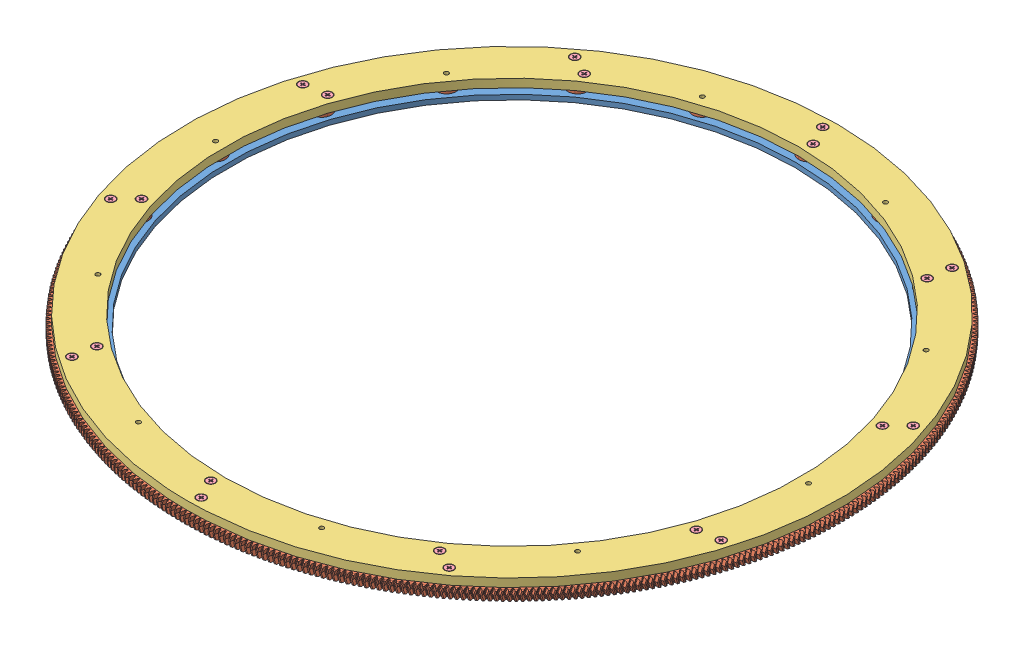
SolidWorks assembly Azimuth Gear, configuration Default. Lengths in mm.
Overall size (765.69 18.86 780.77).
32 component instances, 4 part files, 25 mates.
Components (placement in the parent):
- Center Ring-1: Center Ring [Default] at (-68.2923 13.9978 24.8286) size (660 5 660)
- 450 Teeth Section-1: 450 Teeth Section [Gear Blank] at (-68.2923 16.9978 24.8286) x (0.999972 0 -0.007533) z (0 -1 0) size (199.8 99.77 10.72)
- 450 Teeth Section-2: 450 Teeth Section [Gear Blank] at (-68.2923 16.9978 24.8286) x (0.804566 0 -0.593863) z (0 -1 0) size (199.8 99.77 10.72)
- 450 Teeth Section-3: 450 Teeth Section [Gear Blank] at (-68.2923 16.9978 24.8286) x (0.301844 0 -0.953357) z (0 -1 0) size (199.8 99.77 10.72)
- 450 Teeth Section-4: 450 Teeth Section [Gear Blank] at (-68.2923 16.9978 24.8286) x (-0.316172 0 -0.948702) z (0 -1 0) size (199.8 99.77 10.72)
- 450 Teeth Section-5: 450 Teeth Section [Gear Blank] at (-68.2923 16.9978 24.8286) x (-0.813422 0 -0.581675) z (0 -1 0) size (199.8 99.77 10.72)
- 450 Teeth Section-6: 450 Teeth Section [Gear Blank] at (-68.2923 16.9978 24.8286) x (-0.999972 0 0.007533) z (0 -1 0) size (199.8 99.77 10.72)
- 450 Teeth Section-7: 450 Teeth Section [Gear Blank] at (-68.2923 16.9978 24.8286) x (-0.804566 0 0.593863) z (0 -1 0) size (199.8 99.77 10.72)
- 450 Teeth Section-8: 450 Teeth Section [Gear Blank] at (-68.2923 16.9978 24.8286) x (-0.301844 0 0.953357) z (0 -1 0) size (199.8 99.77 10.72)
- 450 Teeth Section-9: 450 Teeth Section [Gear Blank] at (-68.2923 16.9978 24.8286) x (0.316172 0 0.948702) z (0 -1 0) size (199.8 99.77 10.72)
- 450 Teeth Section-10: 450 Teeth Section [Gear Blank] at (-68.2923 16.9978 24.8286) x (0.813422 0 0.581675) z (0 -1 0) size (199.8 99.77 10.72)
- Spacer ring-1: Spacer ring [Default] at (-68.2923 16.9978 24.8286) size (670 8.5 670)
- flat head screw_am-21: flat head screw_am [B18.6.7M - M4 x 0.7 x 16 Type I Cross Recessed FHMS --16N] at (-375.7267 25.4978 130.2282) x (0 -1 0) z (0 0 1) size (16 8.4 8.4)
- flat head screw_am-22: flat head screw_am [B18.6.7M - M4 x 0.7 x 16 Type I Cross Recessed FHMS --16N] at (-378.9643 25.4978 -70.6068) x (0 -1 0) z (0 0 1) size (16 8.4 8.4)
- flat head screw_am-23: flat head screw_am [B18.6.7M - M4 x 0.7 x 16 Type I Cross Recessed FHMS --16N] at (-263.5358 25.4978 -234.9887) x (0 -1 0) z (0 0 1) size (16 8.4 8.4)
- flat head screw_am-24: flat head screw_am [B18.6.7M - M4 x 0.7 x 16 Type I Cross Recessed FHMS --16N] at (-73.5308 25.4978 -300.1292) x (0 -1 0) z (0 0 1) size (16 8.4 8.4)
- flat head screw_am-25: flat head screw_am [B18.6.7M - M4 x 0.7 x 16 Type I Cross Recessed FHMS --16N] at (118.475 25.4978 -241.1469) x (0 -1 0) z (0 0 1) size (16 8.4 8.4)
- flat head screw_am-26: flat head screw_am [B18.6.7M - M4 x 0.7 x 16 Type I Cross Recessed FHMS --16N] at (239.1421 25.4978 -80.5711) x (0 -1 0) z (0 0 1) size (16 8.4 8.4)
- flat head screw_am-27: flat head screw_am [B18.6.7M - M4 x 0.7 x 16 Type I Cross Recessed FHMS --16N] at (242.3797 25.4978 120.2639) x (0 -1 0) z (0 0 1) size (16 8.4 8.4)
- flat head screw_am-28: flat head screw_am [B18.6.7M - M4 x 0.7 x 16 Type I Cross Recessed FHMS --16N] at (126.9511 25.4978 284.6458) x (0 -1 0) z (0 0 1) size (16 8.4 8.4)
- flat head screw_am-29: flat head screw_am [B18.6.7M - M4 x 0.7 x 16 Type I Cross Recessed FHMS --16N] at (-63.0538 25.4978 349.7863) x (0 -1 0) z (0 0 1) size (16 8.4 8.4)
- flat head screw_am-30: flat head screw_am [B18.6.7M - M4 x 0.7 x 16 Type I Cross Recessed FHMS --16N] at (-255.0596 25.4978 290.804) x (0 -1 0) z (0 0 1) size (16 8.4 8.4)
- flat head screw_am-31: flat head screw_am [B18.6.7M - M4 x 0.7 x 16 Type I Cross Recessed FHMS --16N] at (-359.846 25.4978 114.3909) x (0 -1 0) z (0 0 1) size (16 8.4 8.4)
- flat head screw_am-32: flat head screw_am [B18.6.7M - M4 x 0.7 x 16 Type I Cross Recessed FHMS --16N] at (-356.8077 25.4978 -74.0849) x (0 -1 0) z (0 0 1) size (16 8.4 8.4)
- flat head screw_am-33: flat head screw_am [B18.6.7M - M4 x 0.7 x 16 Type I Cross Recessed FHMS --16N] at (-243.5663 25.4978 -224.7792) x (0 -1 0) z (0 0 1) size (16 8.4 8.4)
- flat head screw_am-34: flat head screw_am [B18.6.7M - M4 x 0.7 x 16 Type I Cross Recessed FHMS --16N] at (-63.3762 25.4978 -280.1318) x (0 -1 0) z (0 0 1) size (16 8.4 8.4)
- flat head screw_am-35: flat head screw_am [B18.6.7M - M4 x 0.7 x 16 Type I Cross Recessed FHMS --16N] at (114.9362 25.4978 -218.9999) x (0 -1 0) z (0 0 1) size (16 8.4 8.4)
- flat head screw_am-36: flat head screw_am [B18.6.7M - M4 x 0.7 x 16 Type I Cross Recessed FHMS --16N] at (223.2614 25.4978 -64.7338) x (0 -1 0) z (0 0 1) size (16 8.4 8.4)
- flat head screw_am-37: flat head screw_am [B18.6.7M - M4 x 0.7 x 16 Type I Cross Recessed FHMS --16N] at (220.2231 25.4978 123.742) x (0 -1 0) z (0 0 1) size (16 8.4 8.4)
- flat head screw_am-38: flat head screw_am [B18.6.7M - M4 x 0.7 x 16 Type I Cross Recessed FHMS --16N] at (106.9816 25.4978 274.4363) x (0 -1 0) z (0 0 1) size (16 8.4 8.4)
- flat head screw_am-39: flat head screw_am [B18.6.7M - M4 x 0.7 x 16 Type I Cross Recessed FHMS --16N] at (-73.2085 25.4978 329.7889) x (0 -1 0) z (0 0 1) size (16 8.4 8.4)
- flat head screw_am-40: flat head screw_am [B18.6.7M - M4 x 0.7 x 16 Type I Cross Recessed FHMS --16N] at (-251.5208 25.4978 268.657) x (0 -1 0) z (0 0 1) size (16 8.4 8.4)
Mates (geometry in assembly coordinates):
- Distance1: distance = 3 mm anti-aligned: plane of Center Ring-1 through (-68.2923 13.9978 24.8286) normal (0 1 0); plane of 450 Teeth Section-1 through (-68.2923 16.9978 24.8286) normal (0 -1 0)
- Concentric1: concentric anti-aligned: circle of Center Ring-1; circle of 450 Teeth Section-1
- Coincident1: coincident anti-aligned: plane of 450 Teeth Section-2 through (132.3859 16.9978 297.2241) normal (0 1 0); plane of Spacer ring-1 through (-68.2923 16.9978 24.8286) normal (0 -1 0)
- Concentric2: concentric anti-aligned: cylinder of Center Ring-1 through (-68.2923 8.9978 24.8286) axis (0 1 0) radius 291; cylinder of Spacer ring-1 through (-68.2923 25.4978 24.8286) axis (0 -1 0) radius 295
- Coincident2: coincident aligned: plane of Center Ring-1 through (-68.2923 13.9978 24.8286) normal (0 0 1); plane of Spacer ring-1 through (-68.2923 16.9978 24.8286) normal (0 0 1)
- Coincident3: coincident aligned: cone of Spacer ring-1 through (-375.7267 25.4978 130.2282) axis (0 -1 0); cone of flat head screw_am-21 through (-375.7267 24.9978 130.2282) axis (0 -1 0)
- Coincident4: coincident aligned: cone of Spacer ring-1 through (-378.9643 25.4978 -70.6068) axis (0 -1 0); cone of flat head screw_am-22 through (-378.9643 24.9978 -70.6068) axis (0 -1 0)
- Coincident5: coincident aligned: cone of Spacer ring-1 through (-263.5358 25.4978 -234.9887) axis (0 -1 0); cone of flat head screw_am-23 through (-263.5358 24.9978 -234.9887) axis (0 -1 0)
- Coincident6: coincident aligned: cone of Spacer ring-1 through (-73.5308 25.4978 -300.1292) axis (0 -1 0); cone of flat head screw_am-24 through (-73.5308 24.9978 -300.1292) axis (0 -1 0)
- Coincident7: coincident aligned: cone of Spacer ring-1 through (118.475 25.4978 -241.1469) axis (0 -1 0); cone of flat head screw_am-25 through (118.475 24.9978 -241.1469) axis (0 -1 0)
- Coincident8: coincident aligned: cone of Spacer ring-1 through (239.1421 25.4978 -80.5711) axis (0 -1 0); cone of flat head screw_am-26 through (239.1421 24.9978 -80.5711) axis (0 -1 0)
- Coincident9: coincident aligned: cone of Spacer ring-1 through (242.3797 25.4978 120.2639) axis (0 -1 0); cone of flat head screw_am-27 through (242.3797 24.9978 120.2639) axis (0 -1 0)
- Coincident10: coincident aligned: cone of Spacer ring-1 through (126.9511 25.4978 284.6458) axis (0 -1 0); cone of flat head screw_am-28 through (126.9511 24.9978 284.6458) axis (0 -1 0)
- Coincident11: coincident aligned: cone of Spacer ring-1 through (-63.0538 25.4978 349.7863) axis (0 -1 0); cone of flat head screw_am-29 through (-63.0538 24.9978 349.7863) axis (0 -1 0)
- Coincident12: coincident aligned: cone of Spacer ring-1 through (-255.0596 25.4978 290.804) axis (0 -1 0); cone of flat head screw_am-30 through (-255.0596 24.9978 290.804) axis (0 -1 0)
- Coincident13: coincident aligned: cone of Spacer ring-1 through (-359.846 25.4978 114.3909) axis (0 -1 0); cone of flat head screw_am-31 through (-359.846 24.9978 114.3909) axis (0 -1 0)
- Coincident14: coincident aligned: cone of Spacer ring-1 through (-356.8077 25.4978 -74.0849) axis (0 -1 0); cone of flat head screw_am-32 through (-356.8077 24.9978 -74.0849) axis (0 -1 0)
- Coincident15: coincident aligned: cone of Spacer ring-1 through (-243.5663 25.4978 -224.7792) axis (0 -1 0); cone of flat head screw_am-33 through (-243.5663 24.9978 -224.7792) axis (0 -1 0)
- Coincident16: coincident aligned: cone of Spacer ring-1 through (-63.3762 25.4978 -280.1318) axis (0 -1 0); cone of flat head screw_am-34 through (-63.3762 24.9978 -280.1318) axis (0 -1 0)
- Coincident17: coincident aligned: cone of Spacer ring-1 through (114.9362 25.4978 -218.9999) axis (0 -1 0); cone of flat head screw_am-35 through (114.9362 24.9978 -218.9999) axis (0 -1 0)
- Coincident18: coincident aligned: cone of Spacer ring-1 through (223.2614 25.4978 -64.7338) axis (0 -1 0); cone of flat head screw_am-36 through (223.2614 24.9978 -64.7338) axis (0 -1 0)
- Coincident19: coincident aligned: cone of Spacer ring-1 through (220.2231 25.4978 123.742) axis (0 -1 0); cone of flat head screw_am-37 through (220.2231 24.9978 123.742) axis (0 -1 0)
- Coincident20: coincident aligned: cone of Spacer ring-1 through (106.9816 25.4978 274.4363) axis (0 -1 0); cone of flat head screw_am-38 through (106.9816 24.9978 274.4363) axis (0 -1 0)
- Coincident21: coincident aligned: cone of Spacer ring-1 through (-73.2085 25.4978 329.7889) axis (0 -1 0); cone of flat head screw_am-39 through (-73.2085 24.9978 329.7889) axis (0 -1 0)
- Coincident22: coincident aligned: cone of Spacer ring-1 through (-251.5208 25.4978 268.657) axis (0 -1 0); cone of flat head screw_am-40 through (-251.5208 24.9978 268.657) axis (0 -1 0)
